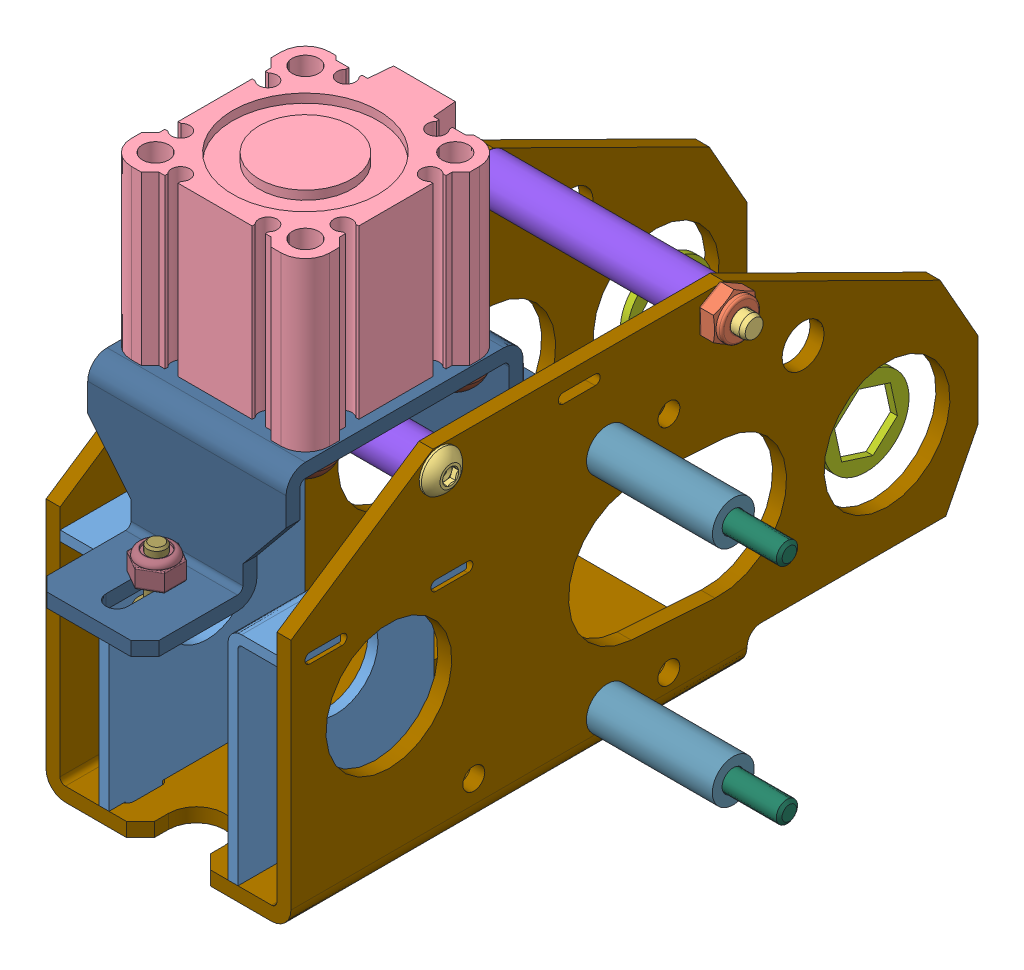
SolidWorks assembly Versa Drop 217-4824, configuration Default. Lengths in mm.
Overall size (104.78 123.93 173.95).
28 component instances, 15 part files, 0 mates.
Components (placement in the parent):
- 217-4824-002 Rev5-1: 217-4824-002 Rev5 [Default] at (-13.4938 -0.6756 -228.1034) x (0 -0.000482 -1) z (-1 0 0) size (44.45 52.01 13.4)
- 217-4824-002 Rev5-2: 217-4824-002 Rev5 [Default] at (13.4938 -0.6756 -228.1034) x (0 0.000482 1) z (1 0 0) size (44.45 52.01 13.4)
- 217-4155-002 Rev3_NNY1032-ZC-1: 217-4155-002 Rev3_NNY1032-ZC [Default] at (-27.7812 45.3882 -239.5431) x (0 0.1393 0.99025) z (-1 0 0) size (9.39 10.84 5)
- 217-4155-002 Rev3_NNY1032-ZC-2: 217-4155-002 Rev3_NNY1032-ZC [Default] at (27.7812 45.3575 -303.0431) x (0 0.863087 0.505056) z (1 0 0) size (9.39 10.84 5)
- 217-4824-004 Rev1_91255A275-1: 217-4824-004 Rev1_91255A275 [Default] at (-27.7812 45.3575 -303.0431) x (0 0.254361 0.967109) z (-1 0 0) size (9.24 9.29 66.65)
- 217-4824-004 Rev1_91255A275-2: 217-4824-004 Rev1_91255A275 [Default] at (27.7812 45.3882 -239.5431) x (0 0.629335 -0.777134) z (1 0 0) size (9.24 9.29 66.65)
- NCQ2A32-15DZ_NCQ2A32-15DZ-1: NCQ2A32-15DZ_NCQ2A32-15DZ [Default] at (0 76.1507 -236.9483) x (-1 0 0) z (0 -1 0) size (45 49.5 38)
  - NCQ2A32-15DZ_CQ2Tube_32-1: NCQ2A32-15DZ_CQ2Tube_32 [Default] at origin size (45 49.5 38)
  - NCQ2A32-15DZ_CQ2 SnapRing_32-1: NCQ2A32-15DZ_CQ2 SnapRing_32 [Default] at (0 0 15.05) size (35.7 35.24 4.9)
- NCQ2A32-15DZ_CQ22031Rods_32-1: NCQ2A32-15DZ_CQ22031Rods_32 [Default] at (0 86.1507 -236.9483) x (-1 0 0) z (0 -1 0) size (32 32 36)
- 217-3257-001 Rev2-1: 217-3257-001 Rev2 [Default] at (-22.225 1.524 -341.122) x (0 -0.198201 -0.980161) z (1 0 0) size (19.5 19.5 1.59)
- 217-3257-001 Rev2-2: 217-3257-001 Rev2 [Default] at (22.225 1.524 -341.122) x (0 -0.304697 -0.952449) z (1 0 0) size (19.5 19.5 1.59)
- 217-3423-010 Rev3-1: 217-3423-010 Rev3 [Default] at (0 45.3575 -303.0431) x (0 0 -1) z (1 0 0) size (9.53 9.53 49.21)
- 217-3423-010 Rev3-2: 217-3423-010 Rev3 [Default] at (0 45.3882 -239.5431) x (0 -0.399936 -0.916543) z (-1 0 0) size (9.53 9.53 49.21)
- 217-4824-015 Rev4-1: 217-4824-015 Rev4 [Default] at (0 1.5242 -341.122) x (0 0.000482 1) z (-1 0 0) size (155.88 78.87 55.56)
- 217-4824-016 Rev1-1: 217-4824-016 Rev1 [Default] at (0 56.7817 -236.9483) x (0 0 1) z (0 -1 0) size (98.24 45 31.38)
- 217-4824-010 Rev1_91255A535-1: 217-4824-010 Rev1_91255A535 [Default] at (-17 51.5112 -253.9483) x (0.026216 0 -0.999656) z (0 -1 0) size (11.17 11.22 13.79)
- 217-4824-010 Rev1_91255A535-2: 217-4824-010 Rev1_91255A535 [Default] at (17 50.2539 -219.9483) x (-0.315041 0 -0.949078) z (0 -1 0) size (11.17 11.22 13.79)
- 217-4824-010 Rev1_91255A535-3: 217-4824-010 Rev1_91255A535 [Default] at (17 50.2539 -253.9483) x (-0.162643 0 -0.986685) z (0 -1 0) size (11.17 11.22 13.79)
- 217-4824-010 Rev1_91255A535-4: 217-4824-010 Rev1_91255A535 [Default] at (-17 50.2539 -219.9483) x (-0.371522 0 -0.928424) z (0 -1 0) size (11.17 11.22 13.79)
- SBS_SBS0832-0500SS-1: SBS_SBS0832-0500SS [Default] at (0 20.6502 -203.2) x (0 1 0) z (0 0 1) size (15.36 8.01 7.99)
- SBS_SBS0832-0500SS-2: SBS_SBS0832-0500SS [Default] at (0 20.6502 -279.4) x (0 1 0) z (0.188455 0 0.982082) size (15.36 8.01 7.99)
- 276-1027-001-1: 276-1027-001 [Default] at (0 28.575 -203.2) size (8.61 5.64 9.94)
- 276-1027-001-2: 276-1027-001 [Default] at (0 28.575 -279.4) x (0.982082 0 -0.188455) z (0.188455 0 0.982082) size (8.61 5.64 9.94)
- 217-3421-005 Rev1-1: 217-3421-005 Rev1 [Default] at (42.0688 30.3203 -277.695) x (0 -0.868908 0.494974) z (-1 0 0) size (9.53 9.53 28.57)
- 217-3421-005 Rev1-2: 217-3421-005 Rev1 [Default] at (42.0688 -20.4797 -277.6705) x (0 -0.158553 0.987351) z (-1 0 0) size (9.53 9.53 28.57)
- SSA_SSA1032-1750ZB-1: SSA_SSA1032-1750ZB [Default] at (24.6062 30.3203 -277.695) x (0 1 0) z (0 0 1) size (7.87 49.28 7.87)
- SSA_SSA1032-1750ZB-2: SSA_SSA1032-1750ZB [Default] at (24.6062 -20.4797 -277.6705) x (0 1 0) z (0 0 1) size (7.87 49.28 7.87)
